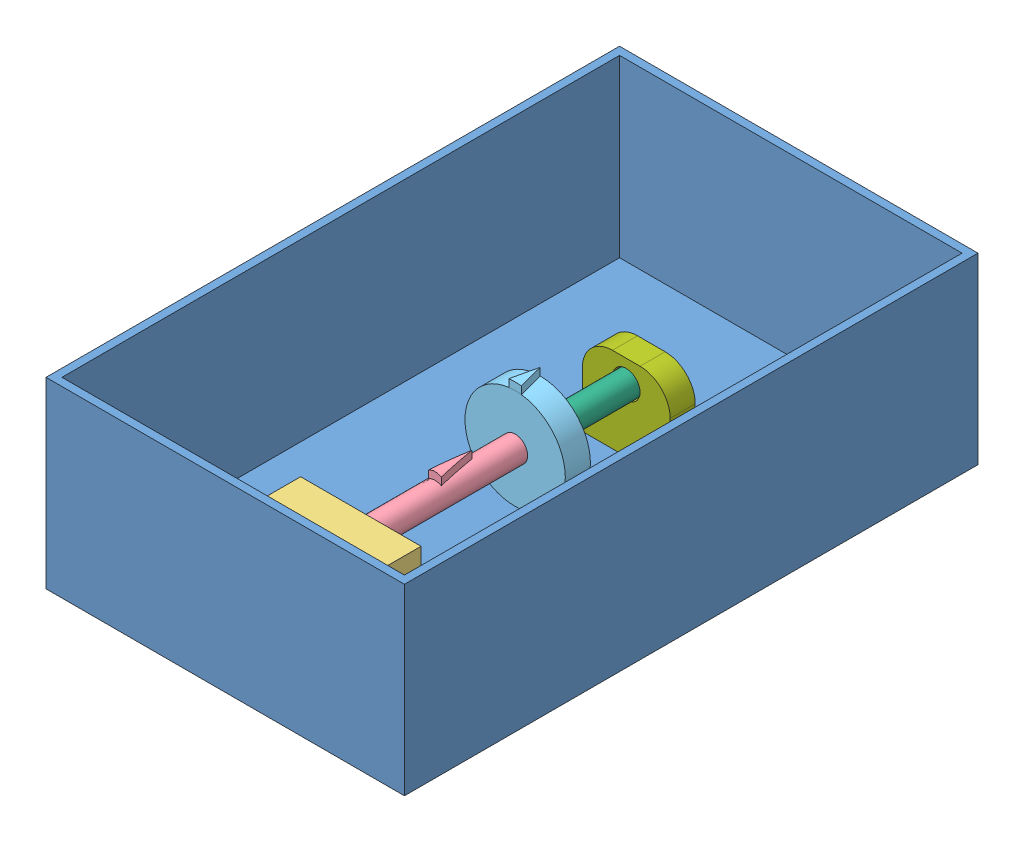
SolidWorks assembly Assembly, configuration Default. Lengths in mm.
Overall size (142.87 99.85 228.6).
8 component instances, 7 part files, 12 mates.
Components (placement in the parent):
- Basic-ForSizing-1: Basic-ForSizing [Default] at (96.8937 80.5573 128.5617) size (142.88 73.02 228.6)
- stepper_holder-1: stepper_holder [Default] at (94.1408 51.6345 190.6846) size (48 64 31.52)
  - Step Motor (28BYJ-48)-1: Step Motor (28BYJ-48) [Varsayılan] at (19.2409 45.9228 39.1125) size (42 61 29.02)
  - stepper_holder_28BYJ-48-1: stepper_holder_28BYJ-48 [Default] at (19.2409 28.9228 46.0671) size (48 34 24)
- axle1-1: axle1 [Default] at (113.3817 105.5573 225.797) x (1 0 0) z (0 1 0) size (10 65 13)
- Wheel-1: Wheel [Default] at (113.3817 105.5573 165.797) x (1 0 0) z (0 1 0) size (40 10 43)
- axle2-1: axle2 [Default] at (113.3817 105.5573 115.797) x (1 0 0) z (0 -1 0) size (10 45 10)
- axle_holder-1: axle_holder [Default] at (112.217 80.5573 120.6559) size (35 34 10)
Mates (geometry in assembly coordinates):
- Coincident1: coincident anti-aligned: plane of Basic-ForSizing-1 through (96.8937 80.5573 128.5617) normal (0 1 0); plane of stepper_holder-1/stepper_holder_28BYJ-48-1 through (113.3817 80.5573 236.7517) normal (0 -1 0)
- Coincident2: coincident anti-aligned: plane of stepper_holder-1/Step Motor (28BYJ-48)-1 through (115.3817 104.0573 219.797) normal (0 -1 0); plane of axle1-1 through (110.8817 104.0573 219.797) normal (0 1 0)
- Coincident3: coincident anti-aligned: plane of stepper_holder-1/Step Motor (28BYJ-48)-1 through (113.3817 105.5573 225.797) normal (0 0 -1); plane of axle1-1 through (113.3817 105.5573 225.797) normal (0 0 1)
- Coincident4: coincident: moEndPointRef_w of stepper_holder-1/Step Motor (28BYJ-48)-1; plane of axle1-1 through (110.8817 107.0573 219.797) normal (1 0 0)
- Coincident5: coincident anti-aligned: plane of axle1-1 through (113.3817 105.5573 165.797) normal (0 0 -1); plane of Wheel-1 through (113.3817 105.5573 165.797) normal (0 0 1)
- Coincident6: coincident anti-aligned: plane of axle1-1 through (111.8817 107.0573 160.797) normal (0 1 0); plane of Wheel-1 through (111.8817 107.0573 155.797) normal (0 -1 0)
- Coincident7: coincident anti-aligned: plane of axle1-1 through (114.8817 104.0573 160.797) normal (1 0 0); plane of Wheel-1 through (114.8817 104.0573 155.797) normal (-1 0 0)
- Coincident8: coincident anti-aligned: plane of Wheel-1 through (113.3817 105.5573 155.797) normal (0 0 -1); plane of axle2-1 through (113.3817 105.5573 155.797) normal (0 0 1)
- Coincident9: coincident anti-aligned: plane of Wheel-1 through (111.8817 104.0573 155.797) normal (0 1 0); plane of axle2-1 through (111.8817 104.0573 160.797) normal (0 -1 0)
- Coincident10: coincident anti-aligned: plane of Wheel-1 through (114.8817 104.0573 155.797) normal (-1 0 0); plane of axle2-1 through (114.8817 107.0573 160.797) normal (1 0 0)
- Concentric1: concentric aligned: circle of axle2-1; circle of axle_holder-1
- Parallel1: parallel anti-aligned: plane of Basic-ForSizing-1 through (96.8937 80.5573 128.5617) normal (0 1 0); plane of axle_holder-1 through (112.217 80.5573 120.6559) normal (0 -1 0)
